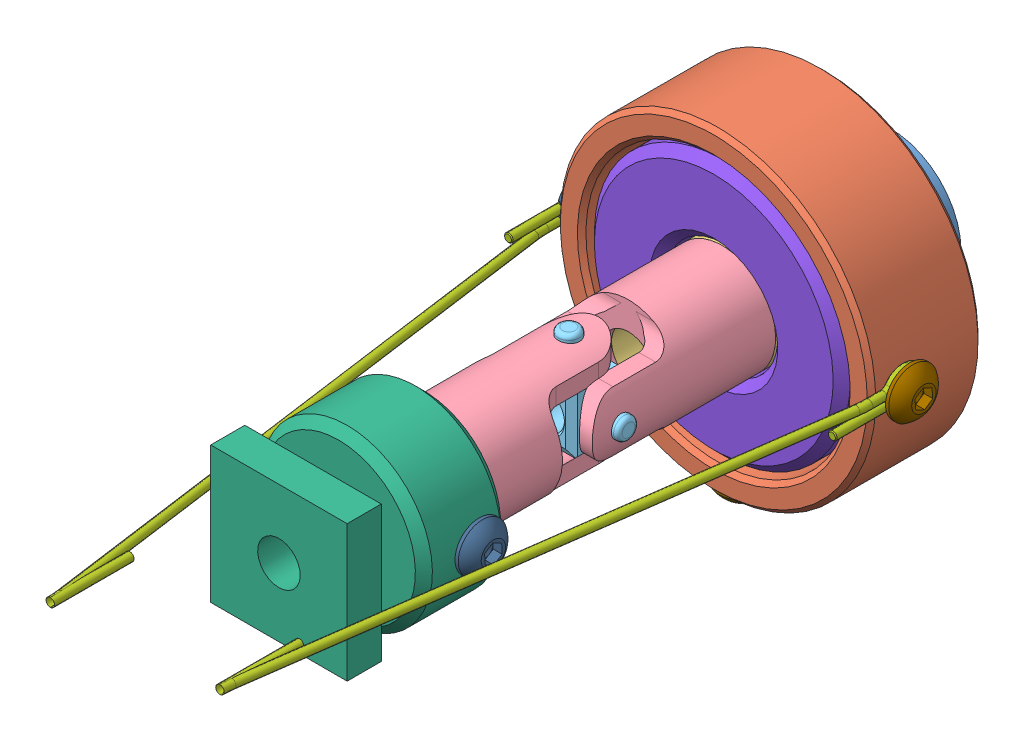
SolidWorks assembly acoplamento, configuration Default. Lengths in mm.
Overall size (41.29 38.65 88.82).
16 component instances, 10 part files, 38 mates.
Components (placement in the parent):
- fixo2_2-1: fixo2_2 [Default] at (0 0 -21.7022) size (30 30 13.5)
- rotativo2_2-1: rotativo2_2 [Default] at (0 0 -23.9522) x (-1 0 0) z (0 -1 0) size (37 13 37)
- encaixe-1: encaixe [Default] at (0 0 -17.9522) x (-1 0 0) z (0 1 0) size (12.5 15 12.5)
- encaixe-2: encaixe [Default] at (0 0 23.0478) x (0 1 0) z (-1 0 0) size (12.5 15 12.5)
- capa-1: capa [Default] at (0 0 -15.4522) x (-1 0 0) z (0 1 0) size (12.5 21.5 12.5)
- capa-2: capa [Default] at (0 0 20.5478) x (0 -1 0) z (1 0 0) size (12.5 21.5 12.5)
- elo-1: elo [Default] at (0 0 5.5478) x (0 1 0) z (-1 0 0) size (14 6 14)
- apoio_acopolamento2_-1: apoio_acopolamento2_ [Default] at (0 0 36.5478) x (1 0 0) z (0 1 0) size (20 17 20)
- cabo-1: cabo [Default] at (-19 -0.55 -14.9522) x (0 1 0) z (0 0 1) size (5.66 24.29 74.07)
- cabo-2: cabo [Default] at (18.992 0.55 -14.9522) x (0 -1 0) z (0 0 1) size (5.66 24.29 74.07)
- anel-1: anel [Default] at (0 0 -17.9522) x (0 -1 0) z (0 0 1) size (30 30 7)
- M3x16-1: M3x16 [ISO 7380 - M3 x 8 --- 8N] at (0 -20.15 -17.9522) x (0 1 0) z (0.994546 0 0.104296) size (18.65 5.7 5.7)
- M3x16-3: M3x16 [ISO 7380 - M3 x 8 --- 8N] at (21.142 0 -17.9522) x (-1 0 0) z (0 -0.083636 0.996496) size (18.65 5.7 5.7)
- Socket Button Head Screw_ISO-6: Socket Button Head Screw_ISO [ISO 7380 - M3 x 8 --- 8N] at (-20.15 0 -17.9522) x (1 0 0) z (0 -0.039508 -0.999219) size (9.65 5.7 5.7)
- Socket Button Head Screw_ISO-7: Socket Button Head Screw_ISO [ISO 7380 - M3 x 8 --- 8N] at (11.65 0 23.0478) x (-1 0 0) z (0 0.88569 -0.464278) size (9.65 5.7 5.7)
- Socket Button Head Screw_ISO-8: Socket Button Head Screw_ISO [ISO 7380 - M3 x 8 --- 8N] at (0 -11.65 23.0478) x (0 1 0) z (0.944352 0 0.328937) size (9.65 5.7 5.7)
Mates (geometry in assembly coordinates):
- Concentric3: concentric aligned: cylinder of encaixe-2; cylinder of capa-2
- Coincident1: coincident anti-aligned: plane of encaixe-2 through (0 0 20.5478) normal (0 0 -1); plane of capa-2 through (0 0 20.5478) normal (0 0 1)
- Concentric4: concentric aligned: cylinder of encaixe-1; cylinder of capa-1
- Coincident2: coincident anti-aligned: plane of encaixe-1 through (0 0 -15.4522) normal (0 0 1); plane of capa-1 through (0 0 -15.4522) normal (0 0 -1)
- Symmetric1: symmetric aligned: plane of capa-2 through (0 0 20.5478) normal (0 -1 0); plane of elo-1 through (0 7 2.5478) normal (0 1 0); plane of elo-1 through (0 -7 2.5478) normal (0 -1 0)
- Concentric6: concentric anti-aligned: cylinder of capa-1; cylinder of elo-1
- Symmetric2: symmetric aligned: plane of capa-1 through (0 0 -15.4522) normal (-1 0 0); plane of elo-1 through (7 0 2.5478) normal (1 0 0); plane of elo-1 through (-7 0 2.5478) normal (-1 0 0)
- Concentric7: concentric anti-aligned: cylinder of fixo2_2-1; cylinder of encaixe-1
- Concentric103: concentric anti-aligned: cylinder of encaixe-2; cylinder of apoio_acopolamento2_-1
- Concentric111: concentric aligned: cylinder of fixo2_2-1; cylinder of rotativo2_2-1
- Concentric112: concentric aligned: cylinder of rotativo2_2-1; cylinder of anel-1
- Concentric113: concentric aligned: cylinder of rotativo2_2-1; cylinder of anel-1
- Width1: width: plane of rotativo2_2-1 through (-8.5 0 -23.9522) normal (0 0 1); plane of anel-1 through (0 0 -21.4522) normal (0 0 -1); plane of fixo2_2-1 through (15 0 -23.7022) normal (0 0 -1); plane of fixo2_2-1 through (6 0 -21.7022) normal (0 0 1)
- Concentric114: concentric aligned: cylinder of encaixe-1; cylinder of anel-1
- Coincident47: coincident anti-aligned: plane of encaixe-2 through (0 0 23.0478) normal (-1 0 0); plane of capa-2 through (0 0 20.5478) normal (1 0 0)
- Concentric115: concentric aligned: cylinder of encaixe-2; cylinder of apoio_acopolamento2_-1
- Tangent4: tangent anti-aligned: cylinder of rotativo2_2-1; cylinder of cabo-2
- Concentric122: concentric anti-aligned: cylinder of rotativo2_2-1; line of cabo-2
- Concentric126: concentric aligned: unknown of rotativo2_2-1
- Tangent12: tangent: face of cabo-2
- Concentric127: concentric aligned: unknown of rotativo2_2-1
- Tangent13: tangent anti-aligned: unknown of rotativo2_2-1
- Concentric128: concentric aligned: unknown of rotativo2_2-1
- Concentric129: concentric aligned: unknown of apoio_acopolamento2_-1
- Tangent15: tangent anti-aligned: unknown of apoio_acopolamento2_-1
- Concentric130: concentric aligned: unknown of apoio_acopolamento2_-1
- Tangent16: tangent anti-aligned: unknown of apoio_acopolamento2_-1
- Concentric131: concentric aligned: cylinder of capa-2; cylinder of elo-1
- Parallel5: parallel aligned: cylinder of capa-1; cylinder of cabo-2
- Concentric134: concentric anti-aligned: cylinder of capa-1; cylinder of capa-2
- Coincident53: coincident aligned: unknown of fixo2_2-1
- Coincident54: coincident anti-aligned: unknown of rotativo2_2-1
- Perpendicular1: perpendicular: unknown of apoio_acopolamento2_-1
- Parallel6: parallel anti-aligned: plane of cabo-1 through (-19 -0.55 -14.9522) normal (0 1 0); plane of cabo-2 through (18.992 0.55 -14.9522) normal (0 -1 0)
- Tangent18: tangent: cylinder of rotativo2_2-1; face of cabo-1
- Tangent22: tangent: edge_curve of cabo-1
- Tangent23: tangent: edge_curve of cabo-1
- Parallel7: parallel aligned: cylinder of cabo-1; cylinder of cabo-2
